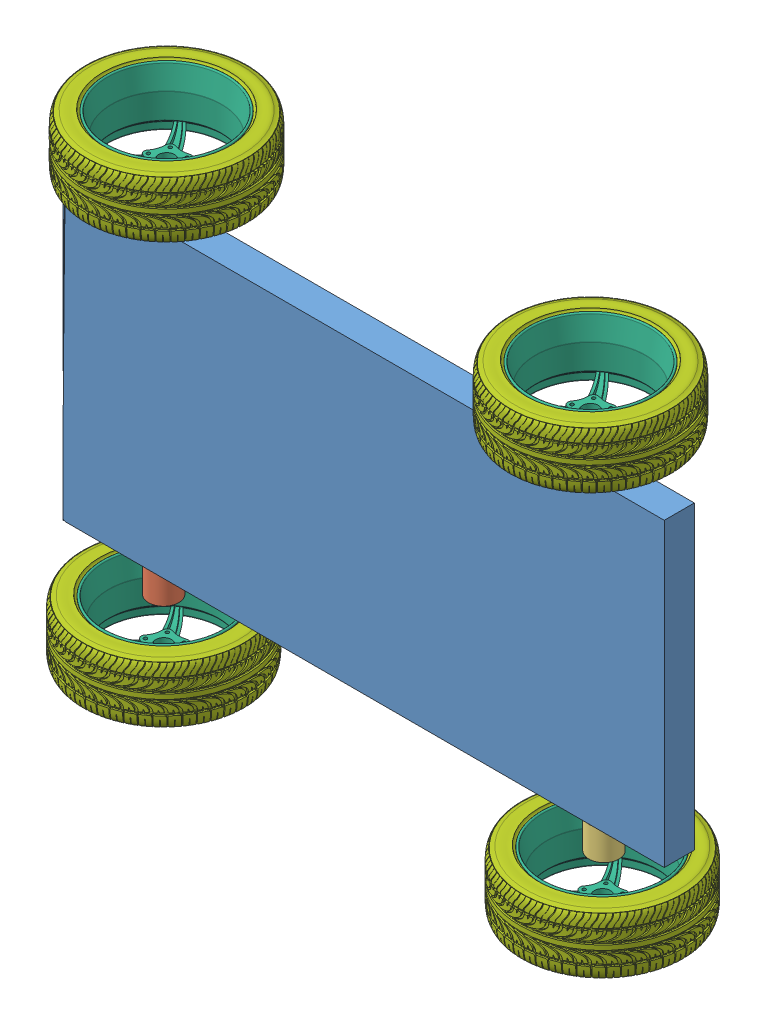
SolidWorks assembly Assem1, configuration Default. Lengths in mm.
Overall size (2791.31 2059.44 980.12).
21 component instances, 8 part files, 12 mates.
Components (placement in the parent):
- Part1-1: Part1 [Default] at (26.6261 -98.4879 81.2881) size (2540.05 1270 127)
- Part2-2: Part2 [Default] at (334.3885 -251.6136 73.4552) x (-0.351375 0 -0.936235) z (0.936235 0 -0.351375) size (127 127 127)
- Part3-1: Part3 [Default] at (2153.0951 -251.6136 119.9339) x (-0.944648 0 -0.328084) z (0.328084 0 -0.944648) size (127 127 127)
- Part4-1: Part4 [Default] at (383.3473 1145.3864 114.9571) x (0.853854 0 -0.520512) z (0.520512 0 0.853854) size (127 127 127)
- Part5-1: Part5 [Default] at (2201.5076 1145.3864 170.0333) size (127 127 127)
- Auton rengas-1: Auton rengas [Default] at (325.6865 -434.6136 138.1054) x (1 0 0) z (0 -1 0) size (939.28 939.28 279.44)
  - vanne-1: vanne [Default] at (0 0 60) x (-0.818413 0.574631 0) z (0 0 1) size (518 518 276.08)
  - rengas-1: rengas [Default] at (0 0 -55) x (-0.896476 -0.443092 0) z (0 0 -1) size (701.17 701.18 256.72)
  - Fefe hubcab-1: Fefe hubcab [Default] at (0 0 58) x (0.973436 0.228959 0) z (0 0 1) size (72 72 26)
- Auton rengas-2: Auton rengas [Default] at (2177.7174 -426.6136 137.5112) x (1 0 0) z (0 -1 0) size (939.28 939.28 279.44)
  - vanne-1: vanne [Default] at (0 0 60) x (-0.818413 0.574631 0) z (0 0 1) size (518 518 276.08)
  - rengas-1: rengas [Default] at (0 0 -55) x (-0.896476 -0.443092 0) z (0 0 -1) size (701.17 701.18 256.72)
  - Fefe hubcab-1: Fefe hubcab [Default] at (0 0 58) x (0.973436 0.228959 0) z (0 0 1) size (72 72 26)
- Auton rengas-3: Auton rengas [Default] at (329.0089 1336.3864 129.0481) x (1 0 0) z (0 -1 0) size (939.28 939.28 279.44)
  - vanne-1: vanne [Default] at (0 0 60) x (-0.818413 0.574631 0) z (0 0 1) size (518 518 276.08)
  - rengas-1: rengas [Default] at (0 0 -55) x (-0.896476 -0.443092 0) z (0 0 -1) size (701.17 701.18 256.72)
  - Fefe hubcab-1: Fefe hubcab [Default] at (0 0 58) x (0.973436 0.228959 0) z (0 0 1) size (72 72 26)
- Auton rengas-4: Auton rengas [Default] at (2150.434 1345.3864 160.2947) x (0.999787 0 -0.020646) z (0 -1 0) size (939.28 939.28 279.44)
  - vanne-1: vanne [Default] at (0 0 60) x (-0.818413 0.574631 0) z (0 0 1) size (518 518 276.08)
  - rengas-1: rengas [Default] at (0 0 -55) x (-0.896476 -0.443092 0) z (0 0 -1) size (701.17 701.18 256.72)
  - Fefe hubcab-1: Fefe hubcab [Default] at (0 0 58) x (0.973436 0.228959 0) z (0 0 1) size (72 72 26)
Mates (geometry in assembly coordinates):
- Coincident1: coincident anti-aligned: plane of Part1-1 through (-29.9796 -124.6136 208.2881) normal (0 -1 0); plane of Part2-2 through (325.6865 -124.6136 138.1054) normal (0 1 0)
- Coincident2: coincident anti-aligned: plane of Part1-1 through (-29.9796 -124.6136 208.2881) normal (0 -1 0); circle of Part3-1
- Coincident3: coincident aligned: plane of Part1-1 through (-29.9796 1145.3864 208.2881) normal (0 1 0); circle of Part4-1
- Coincident4: coincident anti-aligned: plane of Part1-1 through (-29.9796 1145.3864 208.2881) normal (0 1 0); plane of Part5-1 through (2141.7582 1145.3864 148.9817) normal (0 -1 0)
- Concentric2: concentric aligned: circle of Part2-2; circle of Auton rengas-1/rengas-1
- Coincident5: coincident aligned: plane of Part2-2 through (325.6865 -251.6136 138.1054) normal (0 -1 0); circle of Auton rengas-1/rengas-1
- Parallel1: parallel anti-aligned: plane of Part1-1 through (-29.9796 1145.3864 208.2881) normal (0 1 0); plane of Part3-1 through (2192.887 -251.6136 145.8789) normal (0 -1 0)
- Parallel2: parallel anti-aligned: plane of Part1-1 through (-29.9796 1145.3864 208.2881) normal (0 1 0); plane of Part3-1 through (2192.887 -251.6136 145.8789) normal (0 -1 0)
- Coincident9: coincident anti-aligned: plane of Part3-1 through (2192.887 -251.6136 145.8789) normal (0 -1 0); circle of Auton rengas-2/vanne-1
- Tangent6: tangent anti-aligned: plane of Part4-1 through (329.0089 1272.3864 129.0481) normal (0 1 0); sphere of Auton rengas-3/Fefe hubcab-1
- Concentric3: concentric anti-aligned: circle of Part4-1; circle of Auton rengas-3/rengas-1
- Coincident16: coincident anti-aligned: plane of Part5-1 through (2141.7582 1272.3864 148.9817) normal (0 1 0); circle of Auton rengas-4/rengas-1
